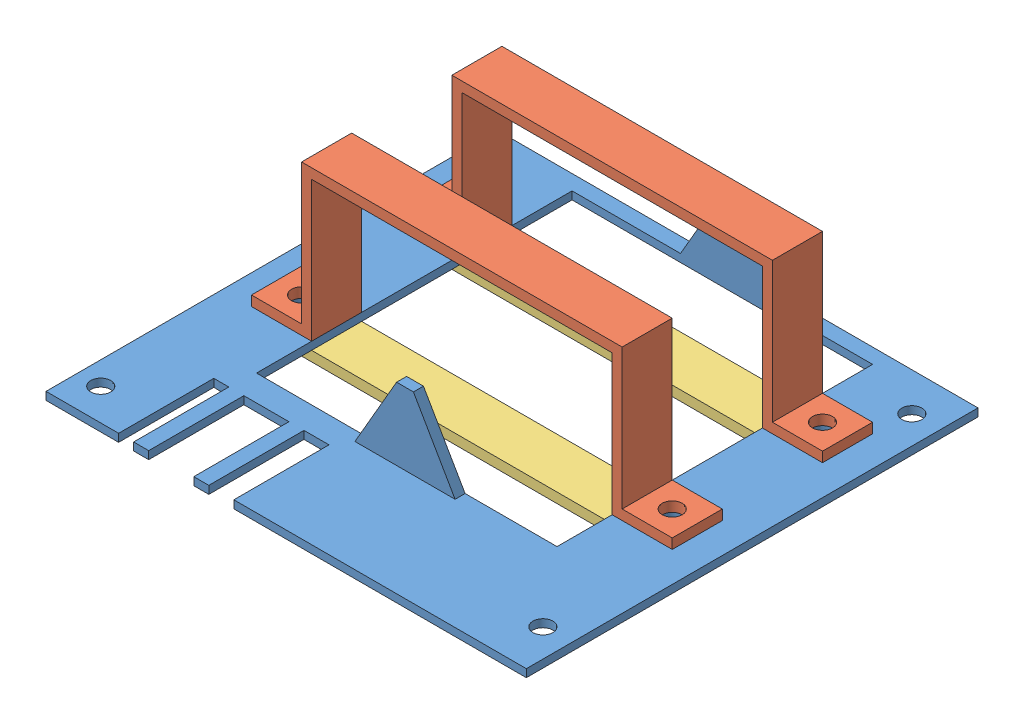
SolidWorks assembly BatteryReverseAssembly, configuration Default. Lengths in mm.
Overall size (95.89 33.57 90.17).
5 component instances, 3 part files, 12 mates.
Components (placement in the parent):
- BatteryReversedBoard-1: BatteryReversedBoard [Default] at (-114.2781 54.7001 199.2867) size (95.89 15.98 90.17)
- BatteryHolder-1: BatteryHolder [Default] at (-92.7436 77.6234 105.5677) size (84 30 10)
- BatteryHolderRear-1: BatteryHolderRear [Default] at (-76.313 52.7001 141.3991) x (1 0 0) z (0 1 0) size (84 10 2)
- BatteryHolder-2: BatteryHolder [Default] at (-92.7436 77.6234 135.5677) size (84 30 10)
- BatteryHolderRear-2: BatteryHolderRear [Default] at (-76.313 54.7001 109.7363) x (1 0 0) z (0 -1 0) size (84 10 2)
Mates (geometry in assembly coordinates):
- Coincident1: coincident anti-aligned: plane of BatteryReversedBoard-1 through (-114.2781 56.2701 199.2867) normal (0 1 0); plane of BatteryHolder-1 through (-130.1721 56.2701 115.5677) normal (0 -1 0)
- Concentric1: concentric aligned: cylinder of BatteryReversedBoard-1 through (-61.1721 33.2701 110.5677) axis (0 1 0) radius 2; cylinder of BatteryHolder-1 through (-61.1721 48.2701 110.5677) axis (0 1 0) radius 2
- Coincident3: coincident aligned: circle of BatteryReversedBoard-1; cylinder of BatteryHolder-1 through (-135.1721 48.2701 110.5677) axis (0 1 0) radius 2
- Coincident4: coincident aligned: circle of BatteryReversedBoard-1; cylinder of BatteryHolder-2 through (-61.1721 48.2701 140.5677) axis (0 1 0) radius 2
- Coincident5: coincident anti-aligned: plane of BatteryReversedBoard-1 through (-114.2781 56.2701 199.2867) normal (0 1 0); plane of BatteryHolder-2 through (-66.1721 56.2701 145.5677) normal (0 -1 0)
- Concentric2: concentric aligned: cylinder of BatteryReversedBoard-1 through (-135.1721 33.2701 140.5677) axis (0 1 0) radius 2; cylinder of BatteryHolder-2 through (-135.1721 48.2701 140.5677) axis (0 1 0) radius 2
- Coincident7: coincident anti-aligned: plane of BatteryReversedBoard-1 through (-114.2781 54.7001 199.2867) normal (0 -1 0); plane of BatteryHolderRear-2 through (-76.313 54.7001 109.7363) normal (0 1 0)
- Concentric3: concentric anti-aligned: cylinder of BatteryReversedBoard-1 through (-135.1721 33.2701 110.5677) axis (0 1 0) radius 2; cylinder of BatteryHolderRear-2 through (-135.1721 62.7001 110.5677) axis (0 -1 0) radius 2
- Concentric4: concentric anti-aligned: cylinder of BatteryReversedBoard-1 through (-61.1721 33.2701 110.5677) axis (0 1 0) radius 2; cylinder of BatteryHolderRear-2 through (-61.1721 62.7001 110.5677) axis (0 -1 0) radius 2
- Coincident8: coincident anti-aligned: plane of BatteryReversedBoard-1 through (-114.2781 54.7001 199.2867) normal (0 -1 0); plane of BatteryHolderRear-1 through (-76.313 54.7001 141.3991) normal (0 1 0)
- Concentric5: concentric aligned: cylinder of BatteryReversedBoard-1 through (-135.1721 33.2701 140.5677) axis (0 1 0) radius 2; cylinder of BatteryHolderRear-1 through (-135.1721 44.7001 140.5677) axis (0 1 0) radius 2
- Concentric6: concentric aligned: cylinder of BatteryReversedBoard-1 through (-61.1721 33.2701 140.5677) axis (0 1 0) radius 2; cylinder of BatteryHolderRear-1 through (-61.1721 44.7001 140.5677) axis (0 1 0) radius 2
